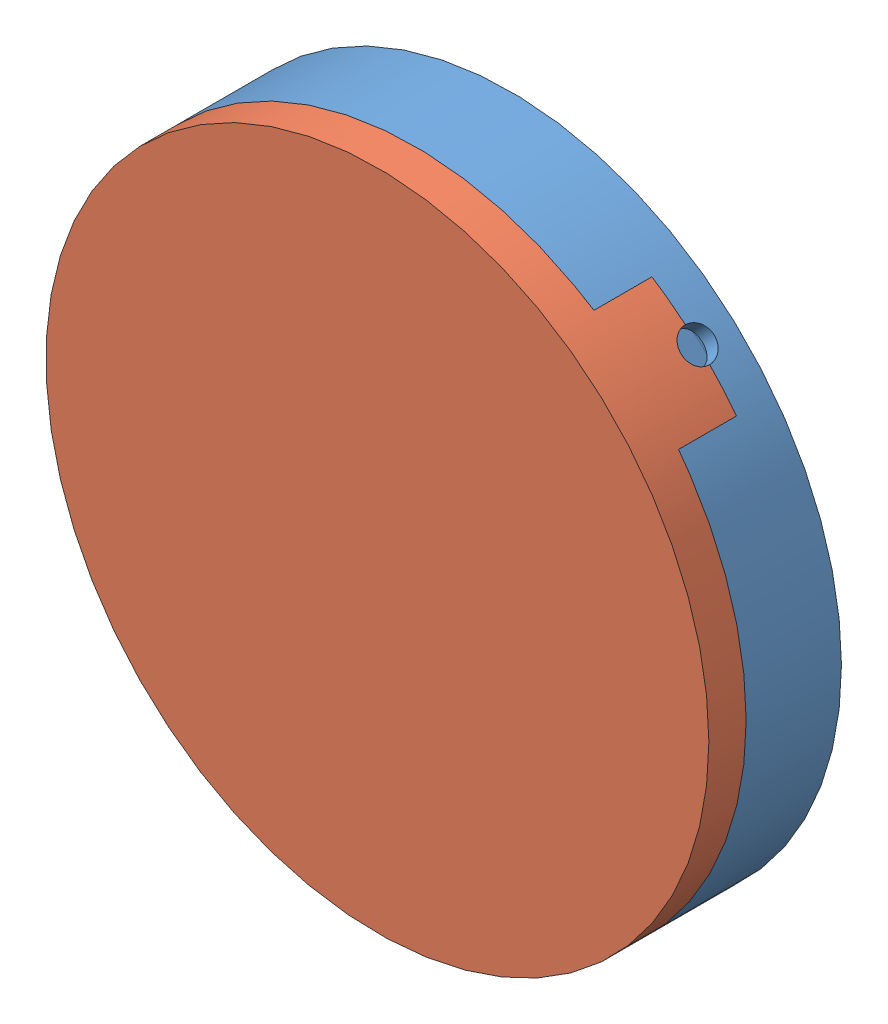
SolidWorks assembly Forma_sestava, configuration Výchozí. Lengths in mm.
Overall size (160 160 32).
2 component instances, 2 part files, 3 mates.
Components (placement in the parent):
- Pulka1-1: Pulka1 [Výchozí] at origin size (160 160 23)
- Pulka2-1: Pulka2 [Výchozí] at origin size (160 160 23.18)
Mates (geometry in assembly coordinates):
- Soustředná1: concentric aligned: circle of Pulka1-1; circle of Pulka2-1
- Sjednocená3: coincident anti-aligned: plane of Pulka1-1 through (-100 99.9315 -5.4) normal (0 0 1); plane of Pulka2-1 through (-100 99.9315 -5.4) normal (0 0 -1)
- Sjednocená4: coincident anti-aligned: plane of Pulka1-1 through (-100 99.9315 -5.4) normal (-0.544639 0.838671 0); plane of Pulka2-1 through (-100 99.9315 -1.4) normal (0.544639 -0.838671 0)
